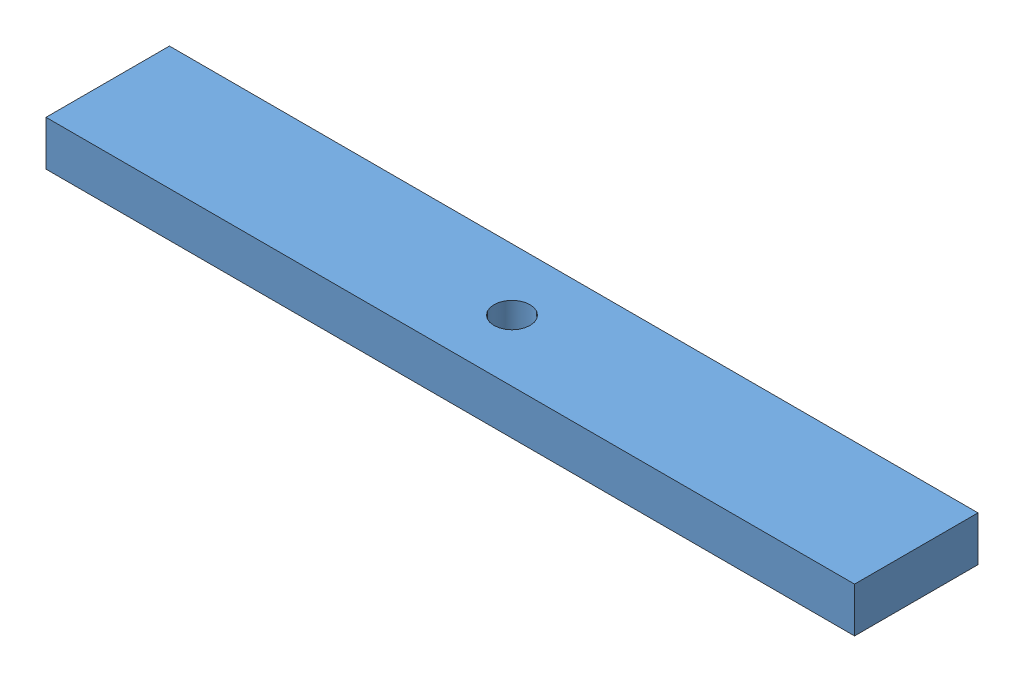
SolidWorks assembly fronthandlesubassembly, configuration Default. Lengths in mm.
Overall size (114.3 6.35 17.45).
2 component instances, 2 part files, 2 mates.
Components (placement in the parent):
- frontplatehandle-1: frontplatehandle [Default] at (35.0533 56.7706 91.5495) size (114.3 6.35 17.45)
- 6079K130-1: 6079K130 [6079K13] at (35.0533 53.5956 91.5495) x (0.9591 0 0.283067) z (0 1 0) (suppressed, hidden)
Mates (geometry in assembly coordinates):
- Concentric1: concentric aligned: circle of frontplatehandle-1; circle of 6079K130-1
- Coincident3: coincident anti-aligned: plane of frontplatehandle-1 through (35.0533 63.1206 91.5495) normal (0 1 0); plane of 6079K130-1 through (36.8507 63.1206 85.4592) normal (0 -1 0)
